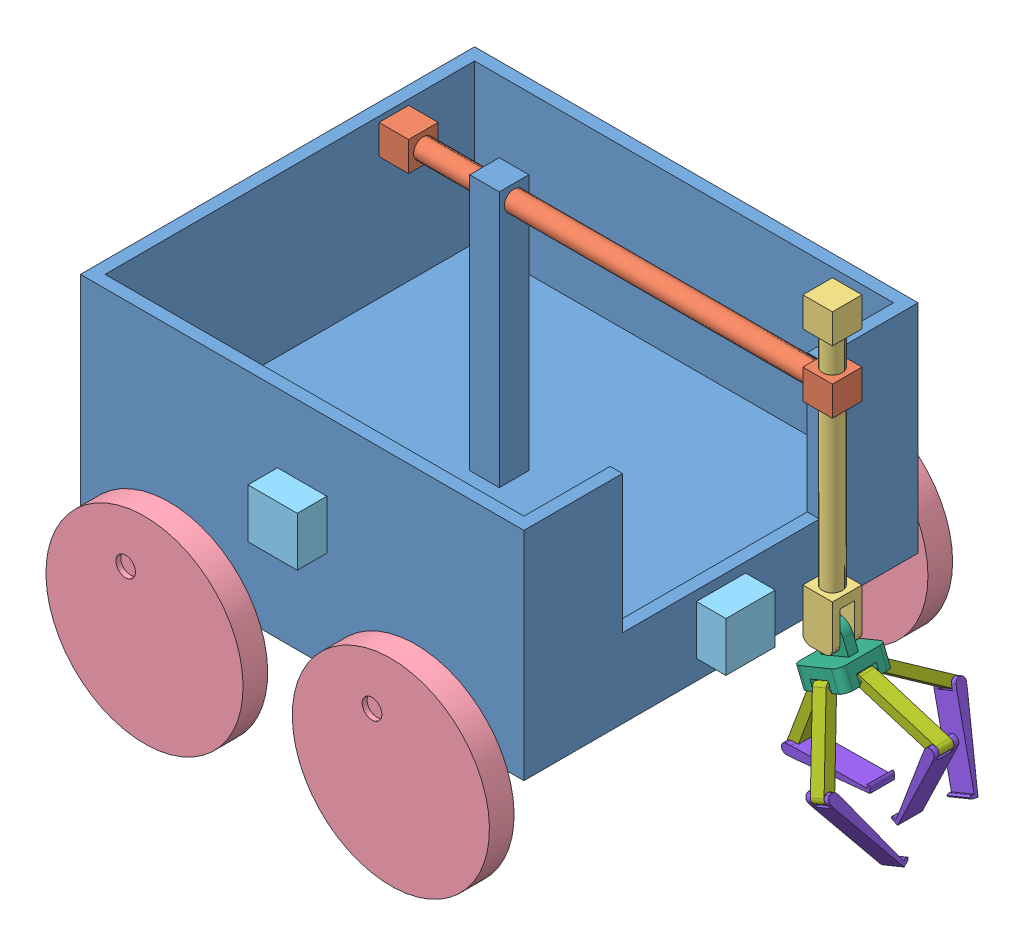
SolidWorks assembly Bot, configuration Default. Lengths in mm.
Overall size (748.27 539.22 693.81).
20 component instances, 8 part files, 23 mates.
Components (placement in the parent):
- Base-1: Base [Default] at (43.8683 39.041 448.8072) size (450 370 400)
- Extension Pole 1-1: Extension Pole 1 [Default] at (-63.1221 344.041 448.8072) x (1 0 0) z (0 0 -1) size (460 30 30)
- Extension Pole 2-1: Extension Pole 2 [Default] at (381.8779 422.5876 448.8072) x (-1 0 0) z (0 0 1) size (30 305 30)
- Wheel-1: Wheel [Default] at (-81.1317 14.041 213.8072) size (200 200 105)
- Wheel-2: Wheel [Default] at (168.8683 14.041 213.8072) size (200 200 105)
- Wheel-3: Wheel [Default] at (-81.1317 14.041 683.8072) x (-0.923728 -0.383049 0) z (0 0 -1) size (200 200 105)
- Wheel-4: Wheel [Default] at (168.8683 14.041 683.8072) x (-0.923728 -0.383049 0) z (0 0 -1) size (200 200 105)
- Camera-1: Camera [Default] at (268.8683 84.041 448.8072) size (30 50 50)
- Camera-2: Camera [Default] at (43.8683 164.041 678.8072) x (0 0 -1) z (1 0 0) size (30 50 50)
- Camera-3: Camera [Default] at (43.8683 164.041 218.8072) x (0 0 1) z (-1 0 0) size (30 50 50)
- Claw Assmbley-1: Claw Assmbley [Default] at (387.2117 60.1777 367.7544) x (0.925743 0.378153 0) z (0 0 1) size (174.25 227.4 154.03)
  - Claw holder-1: Claw holder [Default] at (21.4988 46.7355 81.0528) size (50 100 50)
  - Finger 1-1: Finger 1 [Default] at (-27.5868 0.3014 73.5528) x (0.735853 -0.677142 0) z (0 0 1) size (10 90 15)
  - Finger 2-1: Finger 2 [Default] at (8.9988 -48.6429 130.4696) x (0 0.529318 -0.848423) z (1 0 0) size (11.16 90.09 25)
  - Finger 2-2: Finger 2 [Default] at (-49.9444 -30.7589 68.5528) x (0.325247 0.945629 0) z (0 0 1) size (11.16 90.09 25)
  - Finger 2-3: Finger 2 [Default] at (101.8784 -24.4044 93.5528) x (-0.702007 0.71217 0) z (0 0 -1) size (11.16 90.09 25)
  - Finger 2-4: Finger 2 [Default] at (33.9988 -20.1912 -6.132) x (0 0.189449 0.981891) z (-1 0 0) size (11.16 90.09 25)
  - Finger 1-2: Finger 1 [Default] at (13.9988 -7.3326 118.0844) x (0 -0.375792 -0.926704) z (1 0 0) size (10 90 15)
  - Finger 1-3: Finger 1 [Default] at (74.469 4.4206 73.5528) x (0.632874 0.774255 0) z (0 0 1) size (10 90 15)
  - Finger 1-4: Finger 1 [Default] at (28.9988 7.2269 25.9867) x (0 -0.826651 0.562716) z (-1 0 0) size (10 90 15)
Mates (geometry in assembly coordinates):
- Concentric1: concentric aligned: cylinder of Base-1 through (-81.1317 14.041 316.2336) axis (0 0 -1) radius 15; cylinder of Wheel-1 through (-81.1317 14.041 318.8072) axis (0 0 -1) radius 15
- Distance1: distance = 10 mm anti-aligned: plane of Wheel-1 through (-81.1317 14.041 238.8072) normal (0 0 1); plane of Base-1 through (-181.1317 259.041 248.8072) normal (0 0 -1)
- Concentric2: concentric aligned: cylinder of Base-1 through (168.8683 14.041 316.2336) axis (0 0 -1) radius 15; cylinder of Wheel-2 through (168.8683 14.041 318.8072) axis (0 0 -1) radius 15
- Distance2: distance = 10 mm anti-aligned: plane of Wheel-2 through (168.8683 14.041 238.8072) normal (0 0 1); plane of Base-1 through (-181.1317 259.041 248.8072) normal (0 0 -1)
- Concentric3: concentric aligned: cylinder of Base-1 through (168.8683 14.041 581.3808) axis (0 0 1) radius 15; cylinder of Wheel-4 through (168.8683 14.041 578.8072) axis (0 0 1) radius 15
- Distance3: distance = 10 mm anti-aligned: plane of Wheel-4 through (168.8683 14.041 658.8072) normal (0 0 -1); plane of Base-1 through (-181.1317 259.041 648.8072) normal (0 0 1)
- Concentric4: concentric aligned: cylinder of Base-1 through (-81.1317 14.041 581.3808) axis (0 0 1) radius 15; cylinder of Wheel-3 through (-81.1317 14.041 578.8072) axis (0 0 1) radius 15
- Distance4: distance = 10 mm anti-aligned: plane of Base-1 through (-181.1317 259.041 648.8072) normal (0 0 1); plane of Wheel-3 through (-81.1317 14.041 658.8072) normal (0 0 -1)
- Concentric5: concentric anti-aligned: cylinder of Base-1 through (28.8683 344.041 448.8072) axis (1 0 0) radius 10; cylinder of Extension Pole 1-1 through (366.8779 344.041 448.8072) axis (-1 0 0) radius 10
- Concentric6: concentric anti-aligned: cylinder of Extension Pole 1-1 through (381.8779 387.3253 448.8072) axis (0 -1 0) radius 10; cylinder of Extension Pole 2-1 through (381.8779 167.5876 448.8072) axis (0 1 0) radius 10
- Coincident5: coincident aligned: plane of Base-1 through (43.8683 359.041 448.8072) normal (0 1 0); plane of Extension Pole 1-1 through (-33.1221 359.041 433.8072) normal (0 1 0)
- Distance5: distance = 0 mm anti-aligned: plane of Camera-1 through (268.8683 84.041 448.8072) normal (-1 0 0); plane of Base-1 through (268.8683 259.041 248.8072) normal (1 0 0)
- Distance6: distance = 20 mm aligned: plane of Camera-1 through (298.8683 59.041 473.8072) normal (0 -1 0); plane of Base-1 through (43.8683 39.041 448.8072) normal (0 -1 0)
- Distance7: distance = 175 mm aligned: plane of Camera-1 through (298.8683 109.041 423.8072) normal (0 0 -1); plane of Base-1 through (-181.1317 259.041 248.8072) normal (0 0 -1)
- Coincident10: coincident anti-aligned: plane of Base-1 through (-181.1317 259.041 248.8072) normal (0 0 -1); plane of Camera-3 through (43.8683 164.041 248.8072) normal (0 0 1)
- Distance8: distance = 200 mm aligned: plane of Camera-3 through (68.8683 189.041 248.8072) normal (1 0 0); plane of Base-1 through (268.8683 259.041 248.8072) normal (1 0 0)
- Distance9: distance = 100 mm aligned: plane of Base-1 through (43.8683 39.041 448.8072) normal (0 -1 0); plane of Camera-3 through (18.8683 139.041 248.8072) normal (0 -1 0)
- Coincident13: coincident anti-aligned: plane of Base-1 through (-181.1317 259.041 648.8072) normal (0 0 1); plane of Camera-2 through (43.8683 164.041 648.8072) normal (0 0 -1)
- Distance10: distance = 200 mm aligned: plane of Camera-2 through (68.8683 189.041 648.8072) normal (1 0 0); plane of Base-1 through (268.8683 259.041 248.8072) normal (1 0 0)
- Distance11: distance = 100 mm aligned: plane of Camera-2 through (68.8683 139.041 648.8072) normal (0 -1 0); plane of Base-1 through (43.8683 39.041 448.8072) normal (0 -1 0)
- Coincident14: coincident aligned: plane of Extension Pole 1-1 through (396.8779 344.041 448.8072) normal (1 0 0); plane of Extension Pole 2-1 through (396.8779 392.5876 433.8072) normal (1 0 0)
- Concentric7: concentric aligned: cylinder of Extension Pole 2-1 through (381.8779 130.0876 420.094) axis (0 0 1) radius 7.5; cylinder of Claw Assmbley-1/Claw holder-1 through (381.8779 130.0876 422.594) axis (0 0 1) radius 7.5
- Distance12: distance = 2.5 mm anti-aligned: plane of Claw Assmbley-1/Claw holder-1 through (364.2102 133.6727 443.8072) normal (0 0 -1); plane of Extension Pole 2-1 through (396.8779 157.5876 441.3072) normal (0 0 1)
